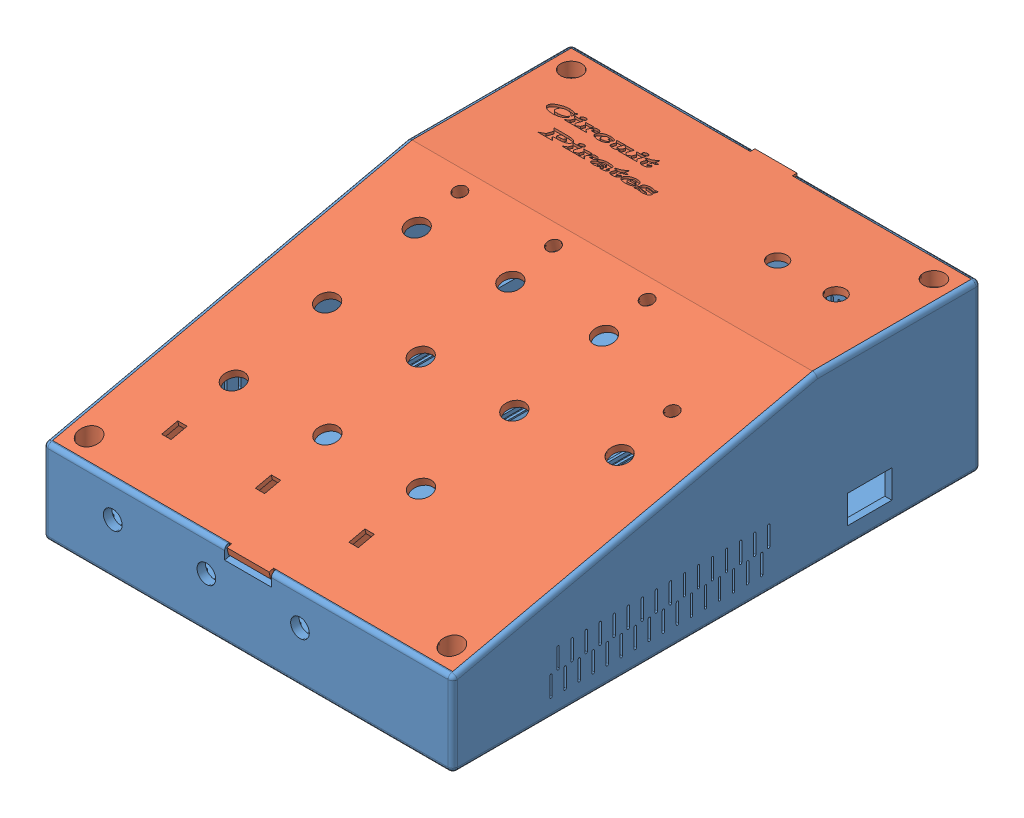
SolidWorks assembly Assem1, configuration Default. Lengths in mm.
Overall size (175 70.81 225.66).
2 component instances, 2 part files, 3 mates.
Components (placement in the parent):
- MainPart-1: MainPart [Default] at origin size (175 70.81 225.66)
- Lid-1: Lid [Default] at (-2 67.8142 2) size (171 44.81 225.62)
Mates (geometry in assembly coordinates):
- Coincident1: coincident anti-aligned: plane of MainPartChanged-1 through (0 67.8142 0) normal (0 1 0); plane of Lid-1 through (-173 67.8142 69.6685) normal (0 -1 0)
- Coincident2: coincident anti-aligned: plane of MainPartChanged-1 through (-173 67.8142 2) normal (0 0 1); plane of Lid-1 through (-173 67.8142 2) normal (0 0 -1)
- Coincident3: coincident anti-aligned: plane of MainPartChanged-1 through (-2 67.8142 70) normal (-1 0 0); plane of Lid-1 through (-2 67.8142 2) normal (1 0 0)
